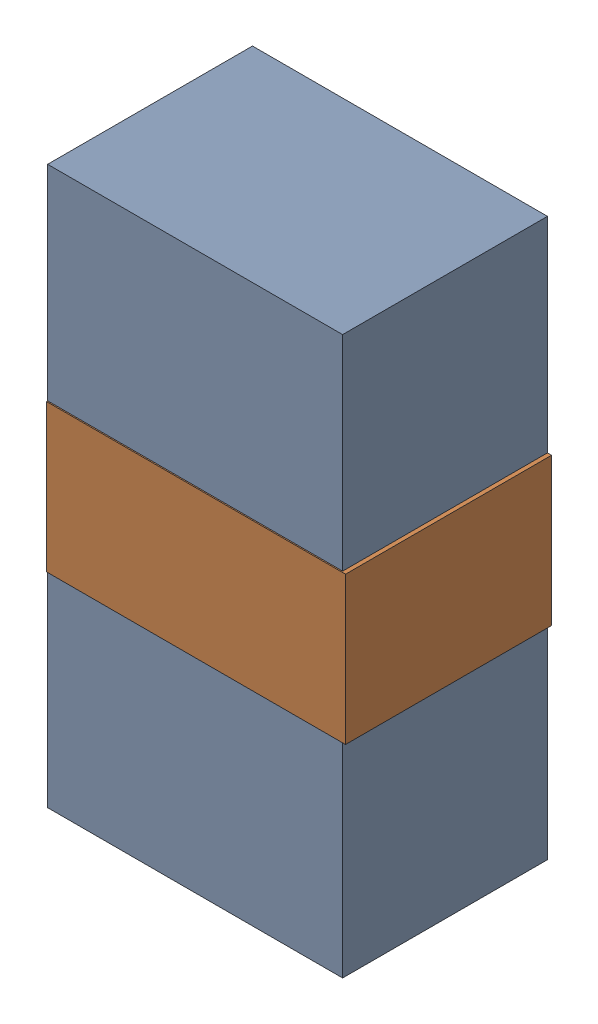
SolidWorks assembly LED2Kanaloa_v2.0.0_Motor, configuration Default. Lengths in mm.
Overall size (1.83 3.4 1.26).
4 component instances, 2 part files, 0 mates.
Components (placement in the parent):
- 334788016-1: 334788016 [Default] at (42.6435 62.738 0) size (1.8 3.4 1.25)
  - Extruded_12-1: Extruded_12 [Default] at origin size (1.8 3.4 1.25)
- 334787760-1: 334787760 [Default] at (42.656 62.738 0) size (1.83 0.9 1.26)
  - Extruded_13-1: Extruded_13 [Default] at origin size (1.83 0.9 1.26)
